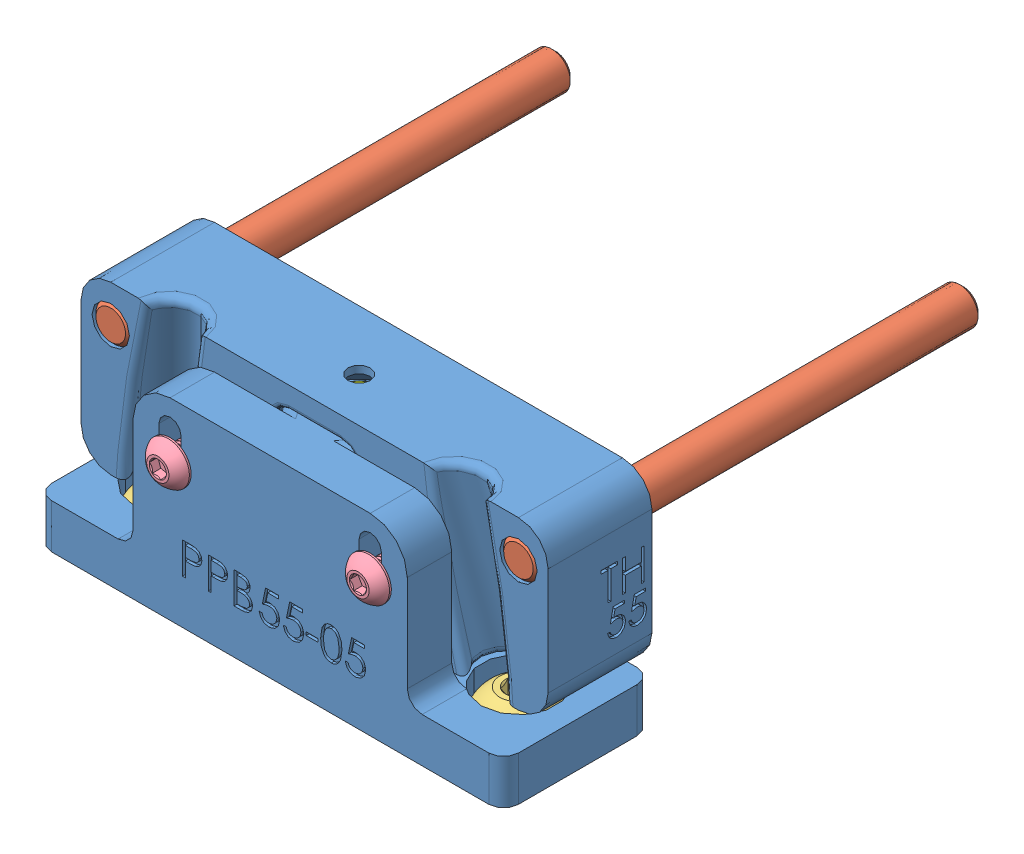
SolidWorks assembly adjustable_parking_post, configuration Default. Lengths in mm.
Overall size (63 34.68 67.77).
14 component instances, 7 part files, 32 mates.
Components (placement in the parent):
- dovetail_parking_post-6: dovetail_parking_post [Parking Post Base] at (31.9041 374.0105 483.3157) x (-1 0 0) z (0 0 -1)
- dowel_pin_5mm_d_60m_l-1: dowel_pin_5mm_d_60m_l [Default] at (27.9041 398.5105 437.3157) x (-0.987123 -0.159963 0) z (0 0 1)
- dowel_pin_5mm_d_60m_l-2: dowel_pin_5mm_d_60m_l [Default] at (-27.0959 398.5105 437.3157) x (-0.123101 0.992394 0) z (0 0 1)
- m5_8mm_buttonhead_screw_92095A207-1: m5_8mm_buttonhead_screw_92095A207 [92095A207] at (23.9041 379.7605 493.3157) x (0.778223 0 0.627988) z (0 1 0)
- m5_8mm_buttonhead_screw_92095A207-2: m5_8mm_buttonhead_screw_92095A207 [92095A207] at (-23.0959 379.7605 493.3157) x (0.778223 0 0.627988) z (0 1 0)
- m3_10mm_buttonhead_screw_92095A182-1: m3_10mm_buttonhead_screw_92095A182 [92095A182] at (13.9041 392.5105 504.9657) x (-0.866025 0.5 0) z (0 0 1)
- m3_heat_set_insert_94180A331-1: m3_heat_set_insert_94180A331 [94180A331] at (13.9041 392.5105 497.3157) x (0.364827 0.931075 0) z (0.931075 -0.364827 0)
- m5_locking_t_nut_20x20_generic-1: m5_locking_t_nut_20x20_generic [Default] at (-20.0959 369.0105 493.3157) x (0 0 1) z (-1 0 0)
- m5_locking_t_nut_20x20_generic-2: m5_locking_t_nut_20x20_generic [Default] at (26.9041 369.0105 493.3157) x (0 0 1) z (-1 0 0)
- dovetail_parking_post-4: dovetail_parking_post [Tool Holder] at (31.9041 372.5105 483.3157) x (-1 0 0) z (0 0 -1)
- m3_heat_set_insert_94180A331-2: m3_heat_set_insert_94180A331 [94180A331] at (-13.0959 392.5105 497.3157) x (-0.287155 -0.957884 0) z (-0.957884 0.287155 0)
- m3_10mm_buttonhead_screw_92095A182-2: m3_10mm_buttonhead_screw_92095A182 [92095A182] at (-13.0959 392.5105 504.9657) x (-0.757956 0.652306 0) z (0 0 1)
- m3_heat_set_insert_94180A331-3: m3_heat_set_insert_94180A331 [94180A331] at (0.4041 400.0105 491.3157) x (-0.759723 0 0.650247) z (-0.650247 0 -0.759723)
- m3_8mm_buttonhead_screw_92095A181-3: m3_8mm_buttonhead_screw_92095A181 [92095A181] at (0.4041 401.6605 491.3157) x (0.786316 0 0.617824) z (0 1 0)
Mates (geometry in assembly coordinates):
- Coincident1594070573: coincident anti-aligned: plane of dovetail_parking_post-6 through (31.9041 377.0105 483.3157) normal (0 1 0); plane of m5_8mm_buttonhead_screw_92095A207-2 through (-26.0789 377.0105 497.0123) normal (0 -1 0)
- Concentric754010035: concentric anti-aligned: cylinder of dovetail_parking_post-6 through (23.9041 380.0105 493.3157) axis (0 -1 0) radius 2.65; circle of m5_8mm_buttonhead_screw_92095A207-1
- Coincident1594070574: coincident anti-aligned: plane of dovetail_parking_post-6 through (31.9041 377.0105 483.3157) normal (0 1 0); plane of m5_8mm_buttonhead_screw_92095A207-1 through (20.9211 377.0105 497.0123) normal (0 -1 0)
- Coincident15940706041: coincident anti-aligned: plane of parking_post-1 through (4.4041 401.0105 491.5157) normal (0 0 1); plane of m3_stainless_steel_washer_90965A130-1 through (0.4041 392.3382 491.5157) normal (0 0 -1)
- Concentric7540100641: concentric anti-aligned: cylinder of m3_stainless_steel_washer_90965A130-1 through (10.4041 392.3382 492.1157) axis (0 0 -1) radius 1.6; cylinder of m3_10mm_buttonhead_screw_92095A182-1 through (13.9041 392.5105 504.9657) axis (0 0 1) radius 2.85
- Coincident15940706051: coincident anti-aligned: plane of m3_stainless_steel_washer_90965A130-1 through (10.4041 392.3382 492.1157) normal (0 0 1); plane of m3_10mm_buttonhead_screw_92095A182-1 through (15.3291 394.9787 503.3157) normal (0 0 -1)
- Concentric754010066: concentric anti-aligned: cylinder of dovetail_parking_post-6 through (-23.0959 380.0105 493.3157) axis (0 -1 0) radius 2.65; circle of m5_8mm_buttonhead_screw_92095A207-2
- Concentric754010067: concentric anti-aligned: circle of m5_8mm_buttonhead_screw_92095A207-2; circle of m5_locking_t_nut_20x20_generic-1
- Parallel1: parallel aligned: plane of dovetail_parking_post-6 through (-31.0959 380.0105 483.3157) normal (-1 0 0); plane of m5_locking_t_nut_20x20_generic-1 through (-26.0959 369.0105 493.3157) normal (-1 0 0)
- Coincident1594070604: coincident aligned: plane of m5_8mm_buttonhead_screw_92095A207-2 through (-24.6659 369.0105 495.2613) normal (0 -1 0); plane of m5_locking_t_nut_20x20_generic-1 through (-26.0959 369.0105 495.8157) normal (0 -1 0)
- Concentric754010068: concentric anti-aligned: circle of m5_8mm_buttonhead_screw_92095A207-1; cylinder of m5_locking_t_nut_20x20_generic-2 through (23.9041 373.5105 493.3157) axis (0 1 0) radius 2.1
- Parallel2: parallel aligned: plane of dovetail_parking_post-6 through (31.9041 380.0105 483.3157) normal (1 0 0); plane of m5_locking_t_nut_20x20_generic-2 through (26.9041 369.0105 493.3157) normal (1 0 0)
- Coincident1594070605: coincident aligned: plane of m5_8mm_buttonhead_screw_92095A207-1 through (22.3341 369.0105 495.2613) normal (0 -1 0); plane of m5_locking_t_nut_20x20_generic-2 through (20.9041 369.0105 495.8157) normal (0 -1 0)
- Concentric754010070: concentric anti-aligned: cylinder of dowel_pin_5mm_d_60m_l-2 through (-27.0959 398.5105 497.3157) axis (0 0 -1) radius 2.5; circle of bmg_extruder_parking_post-2
- Coincident1594070606: coincident aligned: plane of dowel_pin_5mm_d_60m_l-2 through (-27.0959 398.5105 497.3157) normal (0 0 1); plane of dovetail_parking_post-4 through (31.9041 372.5105 497.3157) normal (0 0 1)
- Coincident1594070607: coincident aligned: plane of dowel_pin_5mm_d_60m_l-1 through (27.9041 398.5105 497.3157) normal (0 0 1); plane of dovetail_parking_post-4 through (31.9041 372.5105 497.3157) normal (0 0 1)
- Concentric754010073: concentric aligned: cylinder of dovetail_parking_post-4 through (-13.0959 392.5105 490.3157) axis (0 0 1) radius 2.55; circle of m3_heat_set_insert_94180A331-2
- Concentric754010074: concentric aligned: circle of m3_heat_set_insert_94180A331-2; circle of m3_8mm_buttonhead_screw_92095A181-2
- Concentric754010075: concentric aligned: circle of m3_8mm_buttonhead_screw_92095A181-1; circle of m3_heat_set_insert_94180A331-1
- Concentric754010076: concentric aligned: circle of m3_heat_set_insert_94180A331-1; cylinder of dovetail_parking_post-4 through (13.9041 392.5105 490.3157) axis (0 0 1) radius 2.55
- Concentric754010077: concentric anti-aligned: cylinder of dowel_pin_5mm_d_60m_l-1 through (27.9041 398.5105 497.3157) axis (0 0 -1) radius 2.5; cylinder of dovetail_parking_post-4 through (27.9041 398.5105 415.5367) axis (0 0 1) radius 2.525
- Coincident1594070615: coincident aligned: plane of dovetail_parking_post-6 through (31.9041 400.0105 483.3157) normal (0 1 0); plane of m3_heat_set_insert_94180A331-3 through (0.4041 400.0105 491.3157) normal (0 1 0)
- Concentric754010078: concentric anti-aligned: circle of dovetail_parking_post-6; circle of m3_heat_set_insert_94180A331-3
- Concentric7540100791: concentric anti-aligned: cone of m3_heat_set_insert_94180A331-3 through (0.4041 399.6355 491.3157) axis (0 -1 0); cylinder of m3_8mm_buttonhead_screw_92095A181-3 through (0.4041 401.6605 491.3157) axis (0 1 0) radius 2.85
- Coincident15940706161: coincident anti-aligned: plane of m3_heat_set_insert_94180A331-3 through (0.4041 400.0105 491.3157) normal (0 1 0); plane of m3_8mm_buttonhead_screw_92095A181-3 through (-1.3567 400.0105 493.5567) normal (0 -1 0)
- Coincident1594070616: coincident aligned: plane of dovetail_parking_post-4 through (31.9041 372.5105 497.3157) normal (0 0 1); circle of m3_heat_set_insert_94180A331-2
- Coincident1594070617: coincident aligned: plane of m3_heat_set_insert_94180A331-1 through (13.9041 392.5105 497.3157) normal (0 0 1); plane of dovetail_parking_post-4 through (31.9041 372.5105 497.3157) normal (0 0 1)
- Width2: width aligned: plane of dovetail_parking_post-6 through (31.9041 380.0105 483.3157) normal (1 0 0); plane of dovetail_parking_post-6 through (-31.0959 380.0105 483.3157) normal (-1 0 0); plane of dovetail_parking_post-4 through (31.9041 403.5105 415.5367) normal (1 0 0); plane of dovetail_parking_post-4 through (-31.0959 403.5105 415.5367) normal (-1 0 0)
- Coincident1594070618: coincident aligned: plane of dovetail_parking_post-6 through (31.9041 380.0105 483.3157) normal (0 0 -1); plane of dovetail_parking_post-4 through (31.9041 378.5105 483.3157) normal (0 0 -1)
- Coincident1594070619: coincident anti-aligned: plane of dovetail_parking_post-6 through (31.9041 380.0105 503.3157) normal (0 0 1); plane of m3_10mm_buttonhead_screw_92095A182-2 through (-11.2368 394.6707 503.3157) normal (0 0 -1)
- Coincident1594070620: coincident anti-aligned: plane of dovetail_parking_post-6 through (31.9041 380.0105 503.3157) normal (0 0 1); plane of m3_10mm_buttonhead_screw_92095A182-1 through (15.3291 394.9787 503.3157) normal (0 0 -1)
- Distance1: distance = 1 mm anti-aligned: plane of dovetail_parking_post-6 through (31.9041 380.0105 483.3157) normal (0 1 0); plane of dovetail_parking_post-4 through (-31.0959 381.0105 415.5367) normal (0 -1 0)
